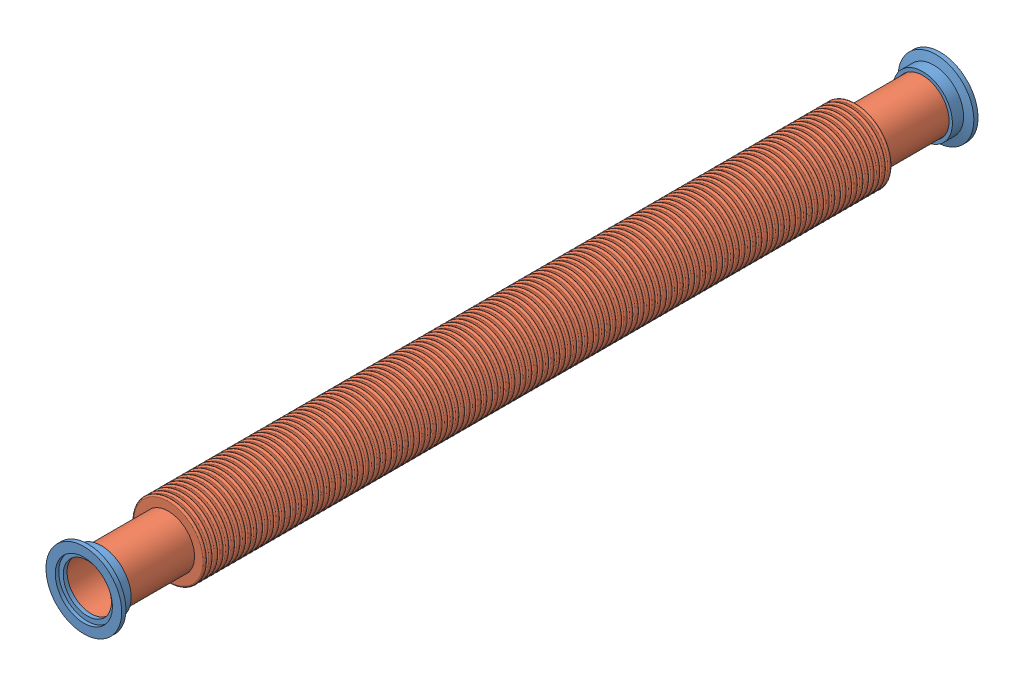
SolidWorks assembly 441525, configuration Default. Lengths in mm.
Overall size (70.05 70.05 620.22).
3 component instances, 2 part files, 2 mates.
Components (placement in the parent):
- 713003-1: 713003 [Default] at (0 0 310.1086) x (0 0 -1) z (0.942415 0.334445 0) size (12.7 54.86 54.86)
- 441541-2: 441541 [Default] at origin size (52.32 52.32 609.6)
- 713003-3: 713003 [Default] at (0 0 -310.1086) x (0 0 1) z (-0.942415 -0.334445 0) size (12.7 54.86 54.86)
Mates (geometry in assembly coordinates):
- Concentric1: concentric aligned: cylinder of 713003-1 through (0 0 310.1086) axis (0 0 1) radius 19.177; cylinder of 441541-2 through (0 0 304.8) axis (0 0 1) radius 19.05
- Coincident1: coincident anti-aligned: plane of 713003-1 through (-5.8402 16.4569 304.8) normal (0 0 -1); plane of 441541-2 through (0 0 304.8) normal (0 0 1)
